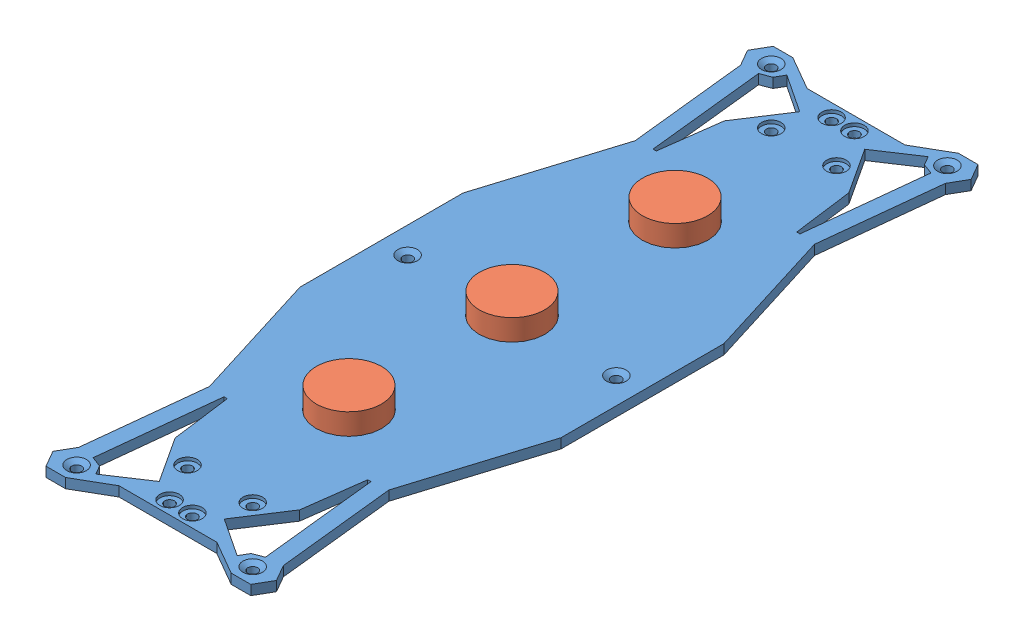
SolidWorks assembly 执行板_电磁铁1.0, configuration 默认. Lengths in mm.
Overall size (80 16.8 223).
4 component instances, 2 part files, 6 mates.
Components (placement in the parent):
- 执行板-1: 执行板 [默认] at (-1.5714 2.2471 223) size (118.32 3 223)
- 电磁铁-1: 电磁铁 [默认] at (-26.8114 -5.1029 236.025) size (44.24 16.8 26.05)
- 电磁铁-2: 电磁铁 [默认] at (-26.8114 -5.1029 186.025) size (44.24 16.8 26.05)
- 电磁铁-3: 电磁铁 [默认] at (-26.8114 -5.1029 286.025) size (44.24 16.8 26.05)
Mates (geometry in assembly coordinates):
- 同心1: concentric: circle of 执行板-1; circle of 电磁铁-1
- 重合1: coincident anti-aligned: plane of 执行板-1 through (-1.5714 2.2471 223) normal (0 -1 0); plane of 电磁铁-1 through (-24.8114 2.2471 236.025) normal (0 1 0)
- 同心2: concentric: circle of 执行板-1; circle of 电磁铁-2
- 重合2: coincident anti-aligned: plane of 执行板-1 through (-1.5714 2.2471 223) normal (0 -1 0); plane of 电磁铁-2 through (-24.8114 2.2471 186.025) normal (0 1 0)
- 同心3: concentric: circle of 执行板-1; circle of 电磁铁-3
- 重合3: coincident anti-aligned: plane of 执行板-1 through (-1.5714 2.2471 223) normal (0 -1 0); plane of 电磁铁-3 through (-24.8114 2.2471 286.025) normal (0 1 0)
